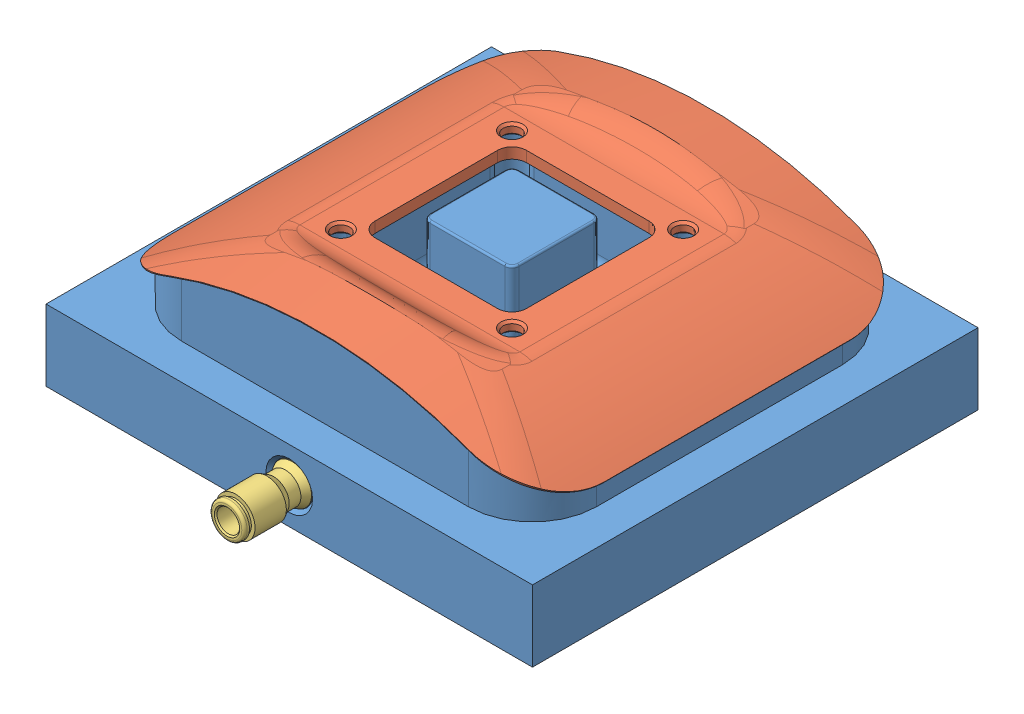
SolidWorks assembly PST Kin Foot Machining, configuration Default. Lengths in mm.
Overall size (136.49 47.93 142.46).
3 component instances, 3 part files, 8 mates.
Components (placement in the parent):
- PST Kin Foot Chuck-1: PST Kin Foot Chuck [Default] at origin size (136.49 46.03 125)
- kin_foot-1: kin_foot [Default] at (0 -113.4858 0) size (123.2 22.06 111.3)
- 5779K140-1: 5779K140 [5779K14] at (0 -28 65.232) x (0.52048 0.853874 0) z (0 0 1) size (10.92 10.92 29.46)
Mates (geometry in assembly coordinates):
- Coincident1: coincident aligned: plane of PST Kin Foot Chuck-1 through (0 0 0) normal (0 0 1); plane of assembly through (0 0 0) normal (0 0 1)
- Coincident2: coincident aligned: plane of PST Kin Foot Chuck-1 through (0 0 0) normal (0 1 0); plane of assembly through (0 0 0) normal (0 1 0)
- Coincident3: coincident aligned: plane of PST Kin Foot Chuck-1 through (0 0 0) normal (1 0 0); plane of assembly through (0 0 0) normal (1 0 0)
- Coincident4: coincident aligned: plane of kin_foot-1 through (0 -113.4858 0) normal (0 0 1); plane of assembly through (0 0 0) normal (0 0 1)
- Coincident5: coincident aligned: plane of kin_foot-1 through (0 -113.4858 0) normal (1 0 0); plane of assembly through (0 0 0) normal (1 0 0)
- Concentric1: concentric aligned: cylinder of PST Kin Foot Chuck-1 through (0 -113.4858 176.2213) axis (0 0 -1) radius 118.5; cylinder of kin_foot-1 through (0 -113.4858 -80.9) axis (0 0 -1) radius 118.95
- Concentric2: concentric aligned: cylinder of PST Kin Foot Chuck-1 through (0 -28 50.5) axis (0 0 1) radius 5.5563; cylinder of 5779K140-1 through (0 -28 65.232) axis (0 0 1) radius 5.461
- Coincident6: coincident anti-aligned: plane of PST Kin Foot Chuck-1 through (0 -28 50.5) normal (0 0 1); plane of 5779K140-1 through (-3.5461 -25.8385 50.5) normal (0 0 -1)
